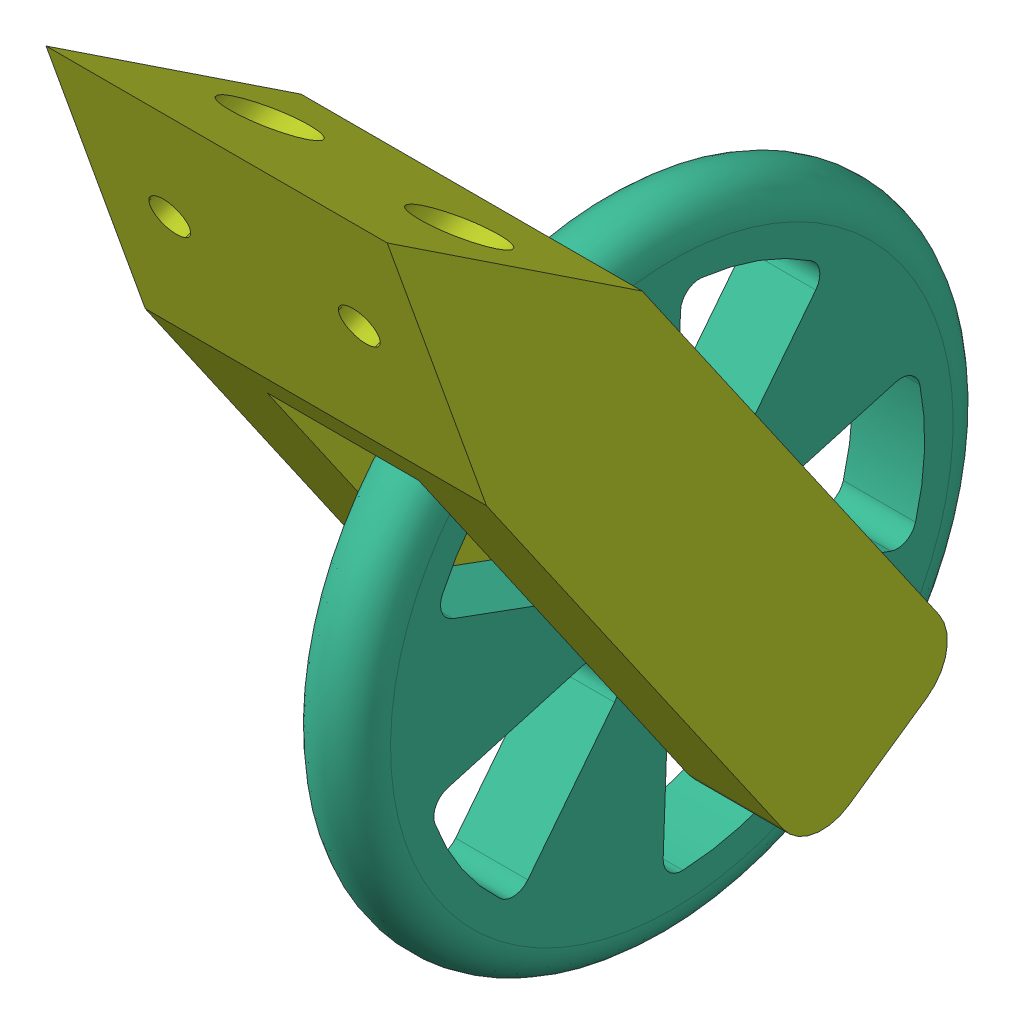
SolidWorks assembly Part_A_FW, configuration Default. Lengths in mm.
Overall size (41 113.84 97.4).
18 component instances, 8 part files, 5 mates.
Components (placement in the parent):
- F684ZZ-1: F684ZZ [Default] at (-37.7065 10.6642 11.5967) size (4 10.3 10.3)
  - _F684ZZ_Outer_Ring_2-1: _F684ZZ_Outer_Ring_2 [Default] at origin size (4 10.3 10.3)
  - _F684ZZ_Inner_Ring_4-1: _F684ZZ_Inner_Ring_4 [Default] x (1 0 0) z (0 -1 0) size (4 5.2 5.2)
  - _F684ZZ_Shield1_6-1: _F684ZZ_Shield1_6 [Default] at (0.5 0 0) x (-1 0 0) z (0 -1 0) size (0.19 8.1 8.1)
  - _F684ZZ_Ball_8-1: _F684ZZ_Ball_8 [Default] at (2 0 3.25) x (1 0 0) z (0 -1 0) size (1.5 1.5 1.5)
  - _F684ZZ_Ball_8-2: _F684ZZ_Ball_8 [Default] at (2 -1.9103 2.6293) x (1 0 0) z (0 -1 0) size (1.5 1.5 1.5)
  - _F684ZZ_Ball_8-3: _F684ZZ_Ball_8 [Default] at (2 -3.0909 1.0043) x (1 0 0) z (0 -1 0) size (1.5 1.5 1.5)
  - _F684ZZ_Ball_8-4: _F684ZZ_Ball_8 [Default] at (2 -3.0909 -1.0043) x (1 0 0) z (0 -1 0) size (1.5 1.5 1.5)
  - _F684ZZ_Ball_8-5: _F684ZZ_Ball_8 [Default] at (2 -1.9103 -2.6293) x (1 0 0) z (0 -1 0) size (1.5 1.5 1.5)
  - _F684ZZ_Ball_8-6: _F684ZZ_Ball_8 [Default] at (2 0 -3.25) x (1 0 0) z (0 -1 0) size (1.5 1.5 1.5)
  - _F684ZZ_Ball_8-7: _F684ZZ_Ball_8 [Default] at (2 1.9103 -2.6293) x (1 0 0) z (0 -1 0) size (1.5 1.5 1.5)
  - _F684ZZ_Ball_8-8: _F684ZZ_Ball_8 [Default] at (2 3.0909 -1.0043) x (1 0 0) z (0 -1 0) size (1.5 1.5 1.5)
  - _F684ZZ_Ball_8-9: _F684ZZ_Ball_8 [Default] at (2 3.0909 1.0043) x (1 0 0) z (0 -1 0) size (1.5 1.5 1.5)
  - _F684ZZ_Ball_8-10: _F684ZZ_Ball_8 [Default] at (2 1.9103 2.6293) x (1 0 0) z (0 -1 0) size (1.5 1.5 1.5)
  - _F684ZZ_Shield2_19-1: _F684ZZ_Shield2_19 [Default] at origin size (0.19 8.1 8.1)
- front_wheel-1: front_wheel [Default] at (-36.2065 10.6642 11.5967) x (1 0 0) z (0 -0.830337 -0.557262) size (7.62 67 67)
- structure_FW-1: structure_FW [Default] at (-28.1241 10.6642 11.5967) x (0 0.822136 0.569292) z (-1 0 0) size (90 20 36)
- shaft_FW-1: shaft_FW [Default] at (-41.1241 10.6642 11.5967) x (1 0 0) z (0 -0.44255 -0.896744) size (36 3.9 3.9)
Mates (geometry in assembly coordinates):
- Concentric4: concentric: cylinder of F684ZZ-1/_F684ZZ_Inner_Ring_4-1 through (-33.7065 10.6642 11.5967) axis (-1 0 0) radius 2; circle of front_wheel-1
- Coincident1: coincident: plane of F684ZZ-1/_F684ZZ_Outer_Ring_2-1 through (-34.7065 15.8142 11.5967) normal (-1 0 0); plane of front_wheel-1 through (-34.7065 8.1008 15.4162) normal (1 0 0)
- Concentric8: concentric: cylinder of F684ZZ-1/_F684ZZ_Inner_Ring_4-1 through (-33.7065 10.6642 11.5967) axis (-1 0 0) radius 2; cylinder of structure_FW-1 through (-54.1241 10.6642 11.5967) axis (1 0 0) radius 2.05
- Coincident2: coincident: plane of structure_FW-1 through (-23.1241 10.6642 11.5967) normal (-1 0 0); plane of shaft_FW-1 through (-23.1241 10.6642 11.5967) normal (1 0 0)
- Concentric9: concentric: cylinder of structure_FW-1 through (-54.1241 10.6642 11.5967) axis (1 0 0) radius 2.05; cylinder of shaft_FW-1 through (-59.1241 10.6642 11.5967) axis (-1 0 0) radius 1.95
